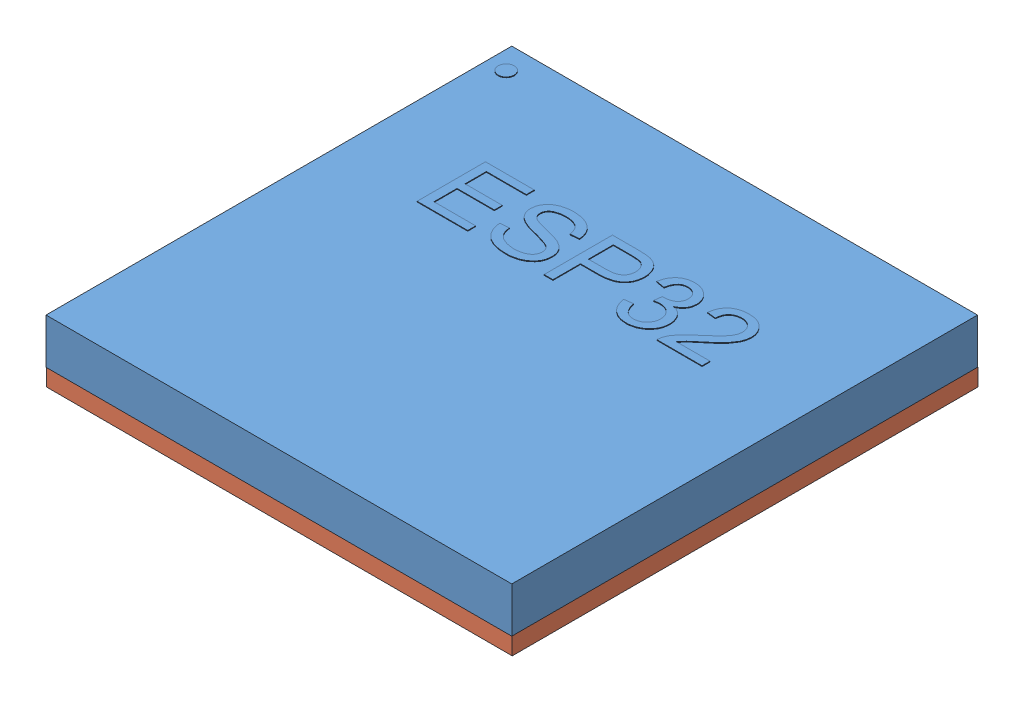
SolidWorks assembly esp32PICO_asm, configuration Défaut. Lengths in mm.
Overall size (7 0.96 7.01).
2 component instances, 2 part files, 1 mates.
Components (placement in the parent):
- esp32pico-3: esp32pico [Défaut] at (-7 -1.3702 3.4301) size (7 0.69 7)
- esp32picolow-3: esp32picolow [Défaut] at (-7 -1.6302 3.4234) size (7 0.27 7)
Mates (geometry in assembly coordinates):
- Coïncidente9: coincident aligned: line of esp32pico-3 through (-7 -1.3702 -3.5699) axis (0 0 1); line of esp32picolow-3 through (-7 -1.3702 -3.5766) axis (0 0 1)
